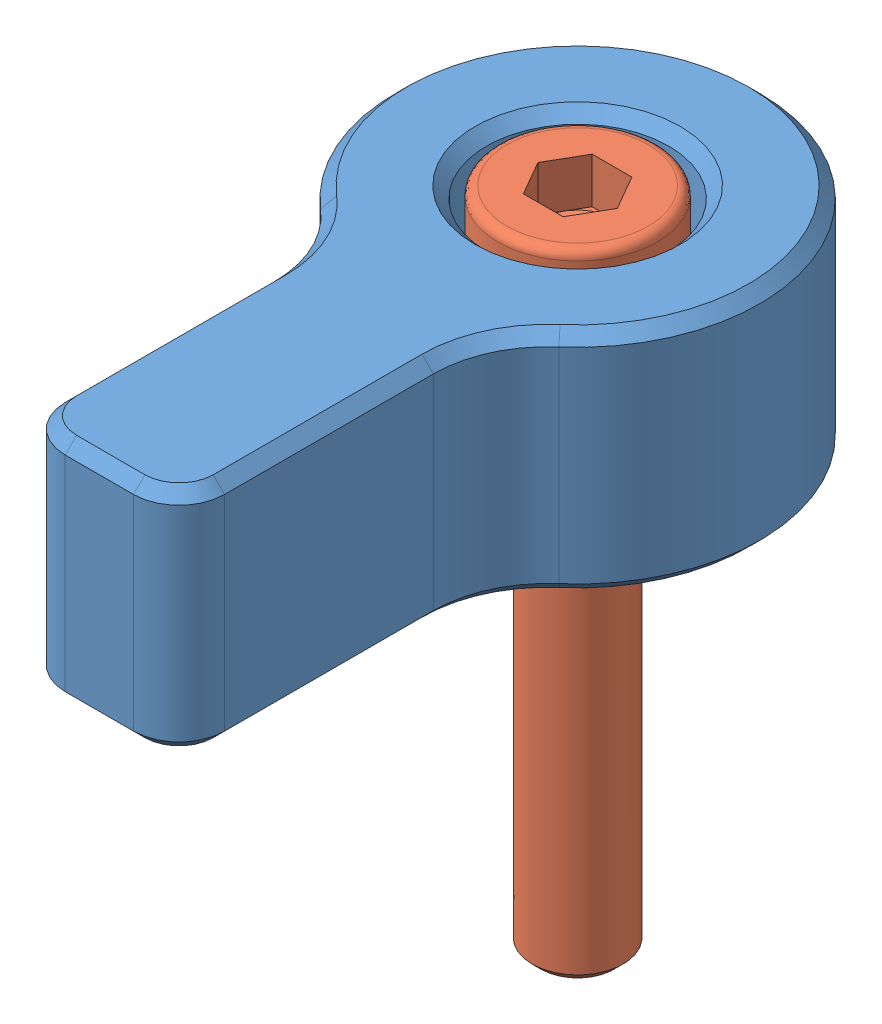
SolidWorks assembly flag_screw, configuration По умолчанию. Lengths in mm.
Overall size (16 29 29).
3 component instances, 3 part files, 4 mates.
Components (placement in the parent):
- flag-1: flag [По умолчанию] at (-48.2962 13.0906 23.7085) size (16 10 29)
- socket head cap screw_din-1: socket head cap screw_din [DIN 912 M4 x 25 --- 25N] at (-48.2962 23.0906 23.7085) x (0 -1 0) z (0 0 1) size (29 7 7)
- plain washer 6902 type abc_din-1: plain washer 6902 type abc_din [DIN 6902-A4.55] at (-48.2962 13.0906 23.7085) x (0 -1 0) z (-0.000413 0 1) size (1 10 10)
Mates (geometry in assembly coordinates):
- Концентричный1: concentric aligned: cylinder of flag-1 through (-48.2962 23.0906 23.7085) axis (0 1 0) radius 4; cylinder of socket head cap screw_din-1 through (-48.2962 54.8406 23.7085) axis (0 1 0) radius 3.5
- Совпадение1: coincident anti-aligned: plane of flag-1 through (-46.0462 19.0906 23.7085) normal (0 1 0); plane of socket head cap screw_din-1 through (-44.7962 19.0906 23.7085) normal (0 -1 0)
- Концентричный2: concentric aligned: cylinder of socket head cap screw_din-1 through (-48.2962 54.8406 23.7085) axis (0 1 0) radius 2; cylinder of plain washer 6902 type abc_din-1 through (-48.2962 12.0906 23.7085) axis (0 1 0) radius 2.275
- Совпадение2: coincident anti-aligned: plane of flag-1 through (-48.2962 13.0906 23.7085) normal (0 -1 0); plane of plain washer 6902 type abc_din-1 through (-48.2962 13.0906 23.7085) normal (0 1 0)
